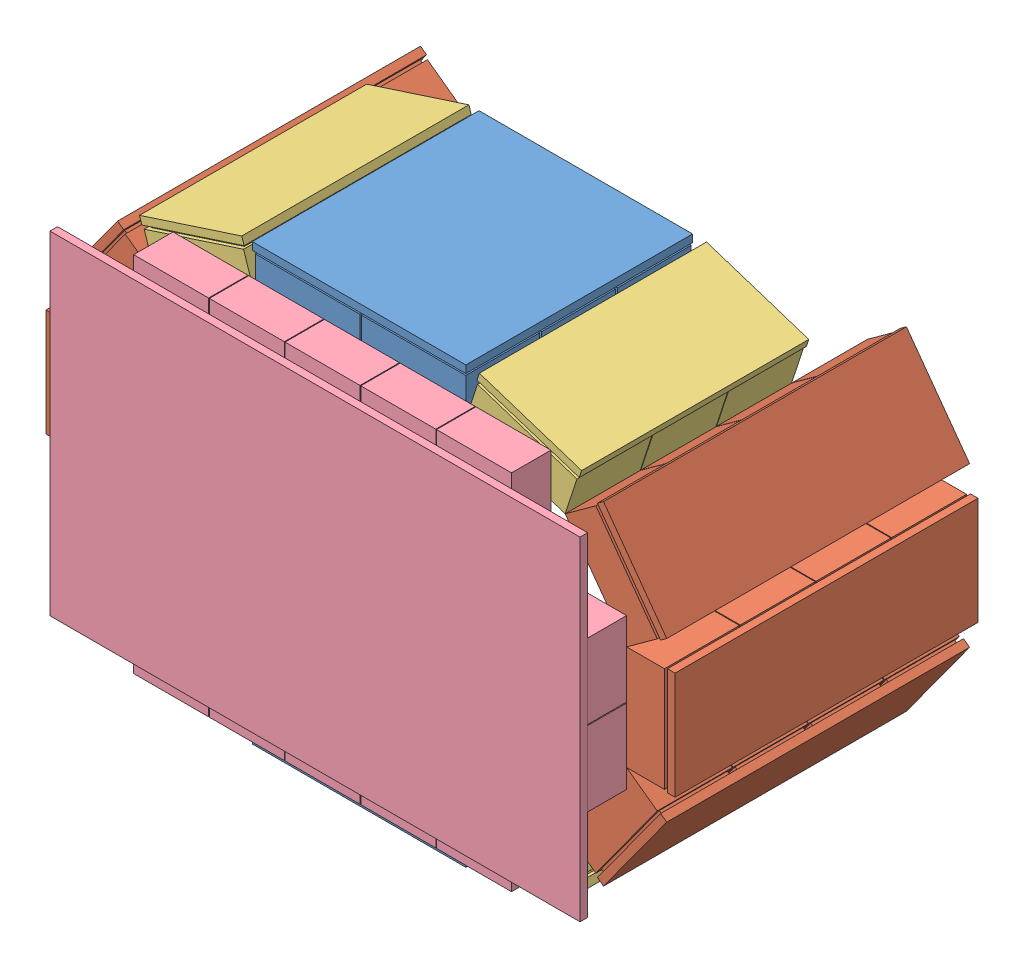
SolidWorks assembly Assem1, configuration Default. Lengths in mm.
Overall size (495.24 340.33 231).
16 component instances, 4 part files, 3 mates.
Components (placement in the parent):
- Detector1n2_changed-1: Detector1n2_changed [Default] at (214.6875 32.8122 259.0633) size (495.24 340.33 200.99)
  - top_bottomDetector2-1: top_bottomDetector2 [Default] at (5.3043 60.2155 74.3483) size (141 32 149.74)
  - CshapedDetector2-1: CshapedDetector2 [Default] at (104.3454 -76.5763 -85.899) x (0.951057 0.309017 0) z (0 0 1) size (177.89 270.84 200)
    - 1Detector-2: 1Detector [Default] at (173.0714 153.2337 184.2598) x (0.809017 0.587785 0) z (0 0 1) size (71 32 200)
    - 1Detector-4: 1Detector [Default] at (223.2683 222.3237 184.2598) x (0.309017 0.951057 0) z (0 0 1) size (71 32 200)
    - 1Detector-5: 1Detector [Default] at (223.2683 307.7237 184.2598) x (-0.309017 0.951057 0) z (0 0 1) size (71 32 200)
    - 1Detector_3modules-1: 1Detector_3modules [Default] at (91.8512 126.8436 209.2598) size (71 32 150)
    - 1Detector_3modules-2: 1Detector_3modules [Default] at (173.0714 376.8138 209.2598) x (-0.809017 0.587785 0) z (0 0 1) size (71 32 150)
  - CshapedDetector2-2: CshapedDetector2 [Default] at (-23.7368 484.2959 -85.899) x (-0.951057 -0.309017 0) z (0 0 1) size (177.89 270.84 200)
    - 1Detector-2: 1Detector [Default] at (173.0714 153.2337 184.2598) x (0.809017 0.587785 0) z (0 0 1) size (71 32 200)
    - 1Detector-4: 1Detector [Default] at (223.2683 222.3237 184.2598) x (0.309017 0.951057 0) z (0 0 1) size (71 32 200)
    - 1Detector-5: 1Detector [Default] at (223.2683 307.7237 184.2598) x (-0.309017 0.951057 0) z (0 0 1) size (71 32 200)
    - 1Detector_3modules-1: 1Detector_3modules [Default] at (91.8512 126.8436 209.2598) size (71 32 150)
    - 1Detector_3modules-2: 1Detector_3modules [Default] at (173.0714 376.8138 209.2598) x (-0.809017 0.587785 0) z (0 0 1) size (71 32 150)
  - top_bottomDetector2-2: top_bottomDetector2 [Default] at (75.3043 347.5042 74.3483) x (-1 0 0) z (0 0 1) size (141 32 149.74)
- Detector3-1: Detector3 [Default] at (255.9219 239.5761 488.4241) x (0 -1 0) z (1 0 0) size (239.5 31 350)
Mates (geometry in assembly coordinates):
- Parallel1: parallel anti-aligned: line of Detector1n2_changed-1/top_bottomDetector2-1 through (185.4918 125.0276 457.4241) axis (1 0 0); line of Detector3-1 through (280.6719 119.1761 457.4241) axis (-1 0 0)
- Perpendicular2: perpendicular: line of Detector1n2_changed-1/CshapedDetector2-1/1Detector-5 through (430.6719 271.172 407.9241) axis (0 0 1); line of Detector3-1 through (430.6719 289.0761 457.4241) axis (0 -1 0)
- Coincident4: coincident anti-aligned: line of Detector1n2_changed-1/CshapedDetector2-1/1Detector-4 through (430.6719 202.172 457.4241) axis (0 1 0); line of Detector3-1 through (430.6719 289.0761 457.4241) axis (0 -1 0)
